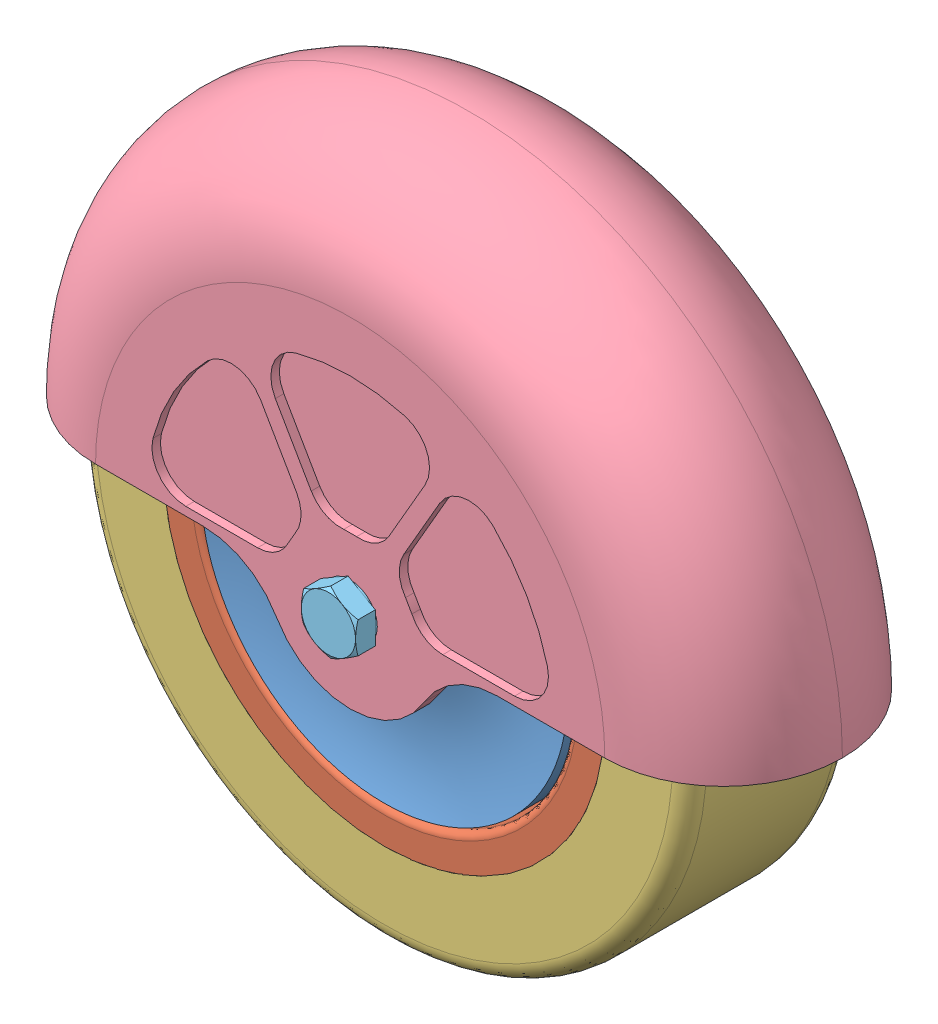
SolidWorks assembly Back Wheel, configuration Default. Lengths in mm.
Overall size (220 200 86.4).
7 component instances, 6 part files, 6 mates.
Components (placement in the parent):
- Castor Wheel-1: Castor Wheel [Default] at origin size (180 180 79.3)
  - Inside 2-1: Inside 2 [Default] at origin size (110.08 110.08 79.3)
  - Inside 1-1: Inside 1 [Default] at origin size (130 130 50)
  - Rubber Wheel-2: Rubber Wheel [Default] at (0 45 25) x (0 0 1) z (-1 0 0) size (50 180 180)
- Wheel Casing-1: Wheel Casing [Default] at (0 0 -10) size (220 135 70)
- hex bolt gradeab_iso-1: hex bolt gradeab_iso [ISO 4014 - M10 x 80 x 26-C] at (0 0 66.4) x (0 0 -1) z (1 0 0) size (86.4 18.48 16)
- hex flange nut gradea_iso-1: hex flange nut gradea_iso [Hexagon Flange Nut ISO - 4161 - M10 - N] at (0 0 -20) x (0.923728 0.383049 0) z (0 0 -1) size (21.8 21.8 10)
Mates (geometry in assembly coordinates):
- Coincident1: coincident: cylinder of Castor Wheel-1/Inside 2-1 through (0 0 0) axis (0 0 1) radius 5; circle of Wheel Casing-1
- Distance2: distance = 5 mm: plane of Castor Wheel-1/Rubber Wheel-2 through (0 0 0) normal (0 0 -1); plane of Wheel Casing-1 through (0 0 -5) normal (0 0 1)
- Concentric1: concentric: cylinder of Wheel Casing-1 through (0 0 -10) axis (0 0 1) radius 5; cylinder of hex bolt gradeab_iso-1 through (0 0 66.4) axis (0 0 1) radius 8
- Coincident13: coincident: plane of Wheel Casing-1 through (0 0 60) normal (0 0 1); plane of hex bolt gradeab_iso-1 through (0 9.2376 60) normal (0 0 -1)
- Concentric2: concentric: cylinder of Wheel Casing-1 through (0 0 -10) axis (0 0 1) radius 5; cylinder of hex flange nut gradea_iso-1 through (0 0 5.0375) axis (0 0 -1) radius 5
- Coincident14: coincident: plane of Wheel Casing-1 through (0 0 -10) normal (0 0 -1); plane of hex flange nut gradea_iso-1 through (3.3173 -7.9997 -10) normal (0 0 1)
